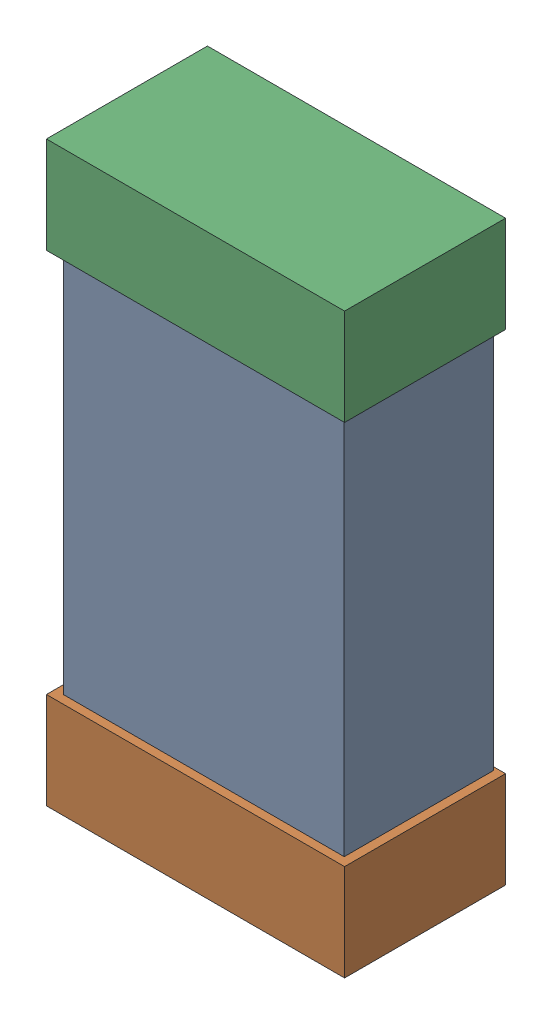
SolidWorks assembly R15, configuration Default. Lengths in mm.
Overall size (0.85 1.65 0.46).
6 component instances, 2 part files, 0 mates.
Components (placement in the parent):
- 432124816_3-1: 432124816_3 [Default] at (28.6501 43.5001 -0.8615) size (0.8 1.5 0.42)
  - Extruded (1)-1: Extruded (1) [Default] at origin size (0.8 1.5 0.42)
- 432138512_6-1: 432138512_6 [Default] at (28.6501 42.8143 -0.8715) size (0.85 0.28 0.46)
  - Extruded-1: Extruded [Default] at origin size (0.85 0.28 0.46)
- 432138512_7-1: 432138512_7 [Default] at (28.6501 44.1859 -0.8715) size (0.85 0.28 0.46)
  - Extruded-1: Extruded [Default] at origin size (0.85 0.28 0.46)
